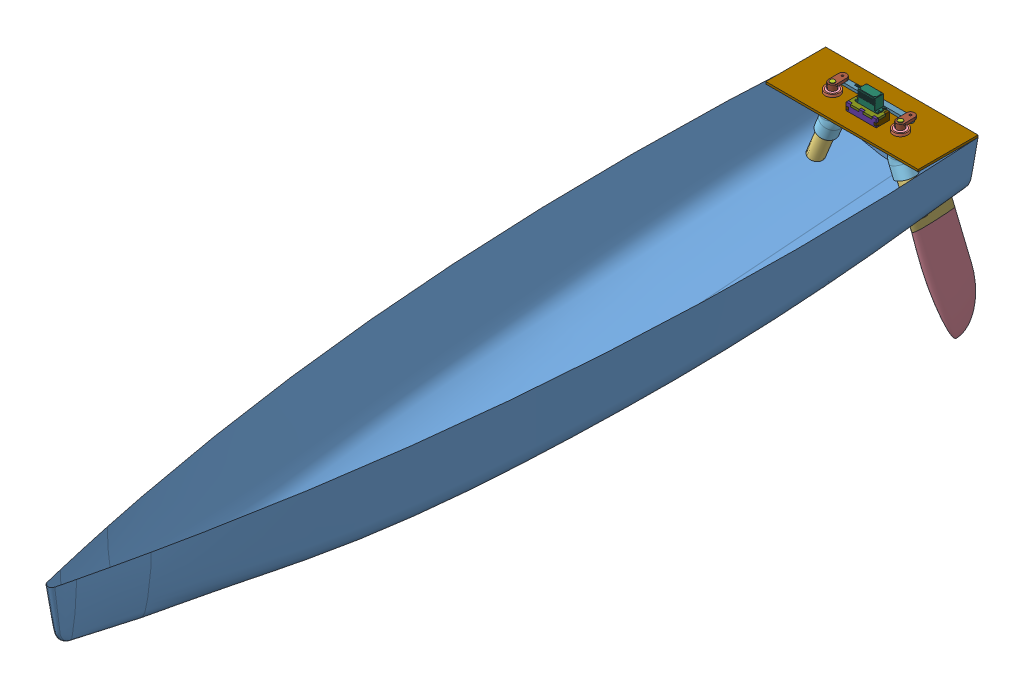
SolidWorks assembly TwinRudderSimpleLinkageDemo, configuration Default. Lengths in mm.
Overall size (425.79 407.28 1993.91).
46 component instances, 18 part files, 54 mates.
Components (placement in the parent):
- Hull-1: Hull [Default] at origin size (385.05 216.07 1993.91)
- BentRudderTube-1: BentRudderTube [Default] at (-0.635 -1.5875 0) size (85.08 167.37 46.84)
  - VerticalPVC-1: VerticalPVC [Default] at (-78.74 -37.7825 82.55) size (33.4 50.8 33.4)
  - AngledPVC-1: AngledPVC [Default] at (-120.3544 -145.3924 82.55) x (0.563065 -0.233229 0.792819) z (-0.732469 0.303399 0.609457) size (33.4 101.6 33.4)
  - UHMW_Bearing-1: UHMW_Bearing [Default] at (-93.1744 -79.7741 82.55) x (0.92154 -0.381714 -0.071118) z (0.065704 -0.027216 0.997468) size (26.92 12.7 26.92)
  - UHMW_Bearing-2: UHMW_Bearing [Default] at (-78.74 -19.9073 82.55) size (26.92 12.7 26.92)
  - UHMW_Bearing-3: UHMW_Bearing [Default] at (-78.74 0.3175 82.55) x (0.941661 0 -0.336564) z (0.336564 0 0.941661) size (26.92 12.7 26.92)
  - 4880K703_STANDARD-WALL WHITE PVC PIPE FITTING-1: 4880K703_STANDARD-WALL WHITE PVC PIPE FITTING [4880K703] at (-78.74 -44.9263 82.55) size (55.36 75.54 43.66)
  - UHMW_Bearing-4: UHMW_Bearing [Default] at (-120.3544 -145.3924 82.55) x (0.92388 -0.382683 0) z (0 0 1) size (26.92 12.7 26.92)
- 60625K950_Ball-And-Socket U-Joint-2: 60625K950_Ball-And-Socket U-Joint [Default] at (-79.375 -46.5138 82.55) x (0 -1 0) z (-0.999815 0 0.019253) size (52.04 20.86 29.99) (flexible)
  - 60625K950_BALL-AND-SOCKET U-JOINT-1: 60625K950_BALL-AND-SOCKET U-JOINT [60625K95] at origin size (29.78 20.07 20.64)
  - 60625K950_BALL-AND-SOCKET U-JOINT-2: 60625K950_BALL-AND-SOCKET U-JOINT [60625K95] x (-0.92388 0.007368 -0.382612) z (0.006807 0.999973 0.002819) size (29.78 20.07 20.64)
  - 60625K950_BALL-AND-SOCKET U-JOINT-3: 60625K950_BALL-AND-SOCKET U-JOINT [Ball] x (0.923905 0 0.382623) z (0.382623 0 -0.923905) size (7.85 16.72 16.72)
- RudderInputShaft-2: RudderInputShaft [Default] at (-79.375 -36.7347 82.55) x (-0.019253 0 -0.999815) z (0.999815 0 -0.019253) size (11.11 63.5 11.11)
- 60625K950_Ball-And-Socket U-Joint-1: 60625K950_Ball-And-Socket U-Joint [Default] at (79.375 -46.5138 82.55) x (0 -1 0) z (0.999815 0 -0.019253) size (52.04 20.86 29.99) (flexible)
  - 60625K950_BALL-AND-SOCKET U-JOINT-1: 60625K950_BALL-AND-SOCKET U-JOINT [60625K95] at origin size (29.78 20.07 20.64)
  - 60625K950_BALL-AND-SOCKET U-JOINT-2: 60625K950_BALL-AND-SOCKET U-JOINT [60625K95] x (-0.92388 0.007368 -0.382612) z (0.006807 0.999973 0.002819) size (29.78 20.07 20.64)
  - 60625K950_BALL-AND-SOCKET U-JOINT-3: 60625K950_BALL-AND-SOCKET U-JOINT [Ball] x (0.923905 0 0.382623) z (0.382623 0 -0.923905) size (7.85 16.72 16.72)
- BentRudderTube-3: BentRudderTube [Default] at (0.635 -1.5875 165.1) x (-1 0 0) z (0 0 -1) size (85.08 167.37 46.84)
  - VerticalPVC-1: VerticalPVC [Default] at (-78.74 -37.7825 82.55) size (33.4 50.8 33.4)
  - AngledPVC-1: AngledPVC [Default] at (-120.3544 -145.3924 82.55) x (0.563065 -0.233229 0.792819) z (-0.732469 0.303399 0.609457) size (33.4 101.6 33.4)
  - UHMW_Bearing-1: UHMW_Bearing [Default] at (-93.1744 -79.7741 82.55) x (0.92154 -0.381714 -0.071118) z (0.065704 -0.027216 0.997468) size (26.92 12.7 26.92)
  - UHMW_Bearing-2: UHMW_Bearing [Default] at (-78.74 -19.9073 82.55) size (26.92 12.7 26.92)
  - UHMW_Bearing-3: UHMW_Bearing [Default] at (-78.74 0.3175 82.55) x (0.941661 0 -0.336564) z (0.336564 0 0.941661) size (26.92 12.7 26.92)
  - 4880K703_STANDARD-WALL WHITE PVC PIPE FITTING-1: 4880K703_STANDARD-WALL WHITE PVC PIPE FITTING [4880K703] at (-78.74 -44.9263 82.55) size (55.36 75.54 43.66)
  - UHMW_Bearing-4: UHMW_Bearing [Default] at (-120.3544 -145.3924 82.55) x (0.92388 -0.382683 0) z (0 0 1) size (26.92 12.7 26.92)
- RudderOutputShaft-1: RudderOutputShaft [Default] at (-125.886 -158.8011 82.55) x (-0.923733 0.382623 0.017788) z (-0.016434 0.006807 -0.999842) size (11.11 111.76 11.11)
- RudderInputShaft-1: RudderInputShaft [Default] at (79.375 -36.7347 82.55) x (0.019253 0 0.999815) z (-0.999815 0 0.019253) size (11.11 63.5 11.11)
- RudderDeck-1: RudderDeck [Default] at (0 0 69.85) size (355.6 5.08 139.7)
- RudderServoHorn-1: RudderServoHorn [Default] at (0 12.4777 82.55) x (-0.999815 0 0.019253) z (0.019253 0 0.999815) size (12.7 6.35 36.7)
- RudderOutputLink-1: RudderOutputLink [Default] at (78.9129 18.8278 58.5544) x (-0.999815 0 0.019253) z (-0.019253 0 -0.999815) size (19.05 12.7 43.05)
- RudderOutputLink-2: RudderOutputLink [Default] at (-79.8371 18.8278 58.5544) x (-0.999815 0 0.019253) z (-0.019253 0 -0.999815) size (19.05 12.7 43.05)
- AssembledRudder-1: AssembledRudder [Default] at (121.3911 -146.9166 104.7715) x (-0.016434 -0.006807 -0.999842) z (0.382683 -0.92388 0) size (103.33 12.91 222.26)
  - RudderAdapter-1: RudderAdapter [Default] at origin size (101.93 12.41 38.1)
  - Rudder-1: Rudder [Default] at (0 0 19.05) size (103.33 12.91 203.25)
- AssembledRudder-2: AssembledRudder [Default] at (-120.6606 -147.2192 104.7715) x (-0.016434 0.006807 -0.999842) z (-0.382683 -0.92388 0) size (103.33 12.91 222.26)
  - RudderAdapter-1: RudderAdapter [Default] at origin size (101.93 12.41 38.1)
  - Rudder-1: Rudder [Default] at (0 0 19.05) size (103.33 12.91 203.25)
- RudderCouplerLink-2: RudderCouplerLink [Default] at (39.2254 12.4777 58.5544) x (-1 0 0) z (0 0 -1) size (92.08 6.35 12.7)
- RudderCouplerLink-3: RudderCouplerLink [Default] at (-40.1496 18.8278 58.5544) x (1 0 0) z (0 0 -1) size (92.08 6.35 12.7)
- RudderOutputShaft-4: RudderOutputShaft [Default] at (125.886 -158.8011 82.55) x (0.923733 0.382623 -0.017788) z (0.016434 0.006807 0.999842) size (11.11 111.76 11.11)
- small rudder servo-1: small rudder servo [Default] at (-10.25 51.7777 72.3) x (1 0 0) z (0 0 -1) size (61.75 42.9 20.5)
- RudderServoBracket-1: RudderServoBracket [Default] at (9.875 17.6978 104.8) x (-1 0 0) z (0 0 -1) size (69.85 5.08 31.75)
- ForwardServoShelfSupport-1: ForwardServoShelfSupport [Default] at (9.875 11.3477 99.72) size (69.85 22.86 5.08)
- SideServoShelfSupport-1: SideServoShelfSupport [Default] at (39.72 11.3477 86.385) x (0 0 -1) z (1 0 0) size (31.75 22.86 5.08)
- SideServoShelfSupport-2: SideServoShelfSupport [Default] at (-25.05 11.3477 86.385) x (0 0 -1) z (1 0 0) size (31.75 22.86 5.08)
Mates (geometry in assembly coordinates):
- Coincident12: coincident aligned: line of Hull-1 through (355.6 177.8 0) axis (0 -1 0); line of RudderDeck-1 through (177.8 0 0) axis (-1 0 0)
- Perpendicular1: perpendicular: plane of RudderDeck-1 through (0 5.08 69.85) normal (0 1 0); plane of Hull-1 through (0 0 0) normal (0 0 1)
- Coincident14: coincident: point of Hull-1; point of RudderDeck-1
- Concentric114: concentric anti-aligned: cylinder of BentRudderTube-3/VerticalPVC-1 through (79.375 11.43 82.55) axis (0 -1 0) radius 16.7005; cylinder of RudderDeck-1 through (79.375 0 82.55) axis (0 1 0) radius 16.7005
- Concentric115: concentric anti-aligned: cylinder of BentRudderTube-1/VerticalPVC-1 through (-79.375 11.43 82.55) axis (0 -1 0) radius 16.7005; cylinder of RudderDeck-1 through (-79.375 0 82.55) axis (0 1 0) radius 16.7005
- Coincident45: coincident aligned: plane of BentRudderTube-1/VerticalPVC-1 through (-79.375 11.43 82.55) normal (0 1 0); plane of BentRudderTube-3/VerticalPVC-1 through (79.375 11.43 82.55) normal (0 1 0)
- Distance1: distance = 6.35 mm aligned: plane of RudderDeck-1 through (0 5.08 69.85) normal (0 1 0); plane of BentRudderTube-3/VerticalPVC-1 through (79.375 11.43 82.55) normal (0 1 0)
- Concentric116: concentric aligned: cylinder of BentRudderTube-3/UHMW_Bearing-3 through (79.375 11.43 82.55) axis (0 -1 0) radius 5.5563; cylinder of RudderInputShaft-1 through (79.375 26.7653 82.55) axis (0 -1 0) radius 5.5563
- Concentric118: concentric aligned: cylinder of BentRudderTube-1/UHMW_Bearing-3 through (-79.375 11.43 82.55) axis (0 -1 0) radius 5.5563; cylinder of RudderInputShaft-2 through (-79.375 26.7653 82.55) axis (0 -1 0) radius 5.5563
- Concentric120: concentric anti-aligned: cylinder of 60625K950_Ball-And-Socket U-Joint-1/60625K950_BALL-AND-SOCKET U-JOINT-1 through (79.375 -36.7347 82.55) axis (0 1 0) radius 5.5563; cylinder of RudderInputShaft-1 through (79.375 26.7653 82.55) axis (0 -1 0) radius 5.5563
- Concentric121: concentric aligned: cylinder of 60625K950_Ball-And-Socket U-Joint-1/60625K950_BALL-AND-SOCKET U-JOINT-1 through (89.4061 -29.1147 82.3568) axis (-0.999815 0 0.019253) radius 1.5602; cylinder of RudderInputShaft-1 through (73.8198 -29.1147 82.657) axis (-0.999815 0 0.019253) radius 1.524
- Concentric122: concentric anti-aligned: cylinder of ? through (-79.375 -21.4947 82.55) axis (0 1 0) radius 9.525; cylinder of RudderInputShaft-2 through (-79.375 26.7653 82.55) axis (0 -1 0) radius 5.5563
- Concentric123: concentric aligned: cylinder of ? through (-89.4061 -29.1147 82.7432) axis (0.999815 0 -0.019253) radius 1.5602; cylinder of RudderInputShaft-2 through (-73.8198 -29.1147 82.443) axis (0.999815 0 -0.019253) radius 1.524
- Coincident48: coincident anti-aligned: plane of BentRudderTube-1/4880K703_STANDARD-WALL WHITE PVC PIPE FITTING-1 through (-79.375 -46.5138 82.55) normal (0 0 1); plane of BentRudderTube-3/4880K703_STANDARD-WALL WHITE PVC PIPE FITTING-1 through (79.375 -46.5138 82.55) normal (0 0 -1)
- Concentric124: concentric aligned: cylinder of 60625K950_Ball-And-Socket U-Joint-1/60625K950_BALL-AND-SOCKET U-JOINT-2 through (88.9494 -69.6283 82.55) axis (0.382683 -0.92388 0) radius 9.525; cylinder of RudderOutputShaft-4 through (83.1173 -55.5484 82.55) axis (0.382683 -0.92388 0) radius 5.5563
- Concentric125: concentric aligned: cylinder of 60625K950_Ball-And-Socket U-Joint-1/60625K950_BALL-AND-SOCKET U-JOINT-2 through (85.8684 -62.6566 72.5186) axis (0.016434 0.006807 0.999842) radius 1.5602; cylinder of RudderOutputShaft-4 through (86.1246 -62.5505 88.1054) axis (0.016434 0.006807 0.999842) radius 1.524
- Concentric126: concentric aligned: cylinder of ? through (-88.9494 -69.6283 82.55) axis (-0.382683 -0.92388 0) radius 9.525; cylinder of RudderOutputShaft-1 through (-83.1173 -55.5484 82.55) axis (-0.382683 -0.92388 0) radius 5.5563
- Concentric127: concentric aligned: cylinder of ? through (-85.8684 -62.6566 92.5814) axis (-0.016434 0.006807 -0.999842) radius 1.5602; cylinder of RudderOutputShaft-1 through (-86.1246 -62.5505 76.9946) axis (-0.016434 0.006807 -0.999842) radius 1.524
- Concentric128: concentric aligned: cylinder of BentRudderTube-1/UHMW_Bearing-1 through (-88.9494 -69.6283 82.55) axis (-0.382683 -0.92388 0) radius 13.462; cylinder of RudderOutputShaft-1 through (-83.1173 -55.5484 82.55) axis (-0.382683 -0.92388 0) radius 5.5563
- Concentric129: concentric aligned: cylinder of BentRudderTube-3/UHMW_Bearing-1 through (88.9494 -69.6283 82.55) axis (0.382683 -0.92388 0) radius 13.462; cylinder of RudderOutputShaft-4 through (83.1173 -55.5484 82.55) axis (0.382683 -0.92388 0) radius 5.5563
- Concentric130: concentric anti-aligned: cylinder of AssembledRudder-1/RudderAdapter-1 through (125.886 -158.8011 82.55) axis (-0.382683 0.92388 0) radius 5.5563; cylinder of RudderOutputShaft-4 through (83.1173 -55.5484 82.55) axis (0.382683 -0.92388 0) radius 5.5563
- Concentric131: concentric aligned: cylinder of AssembledRudder-1/RudderAdapter-1 through (123.8212 -152.7832 104.7715) axis (0.016434 0.006807 0.999842) radius 2.1526; cylinder of RudderOutputShaft-4 through (123.5472 -152.8967 88.1054) axis (0.016434 0.006807 0.999842) radius 1.524
- Concentric132: concentric anti-aligned: cylinder of RudderOutputShaft-1 through (-83.1173 -55.5484 82.55) axis (-0.382683 -0.92388 0) radius 5.5563; cylinder of AssembledRudder-2/RudderAdapter-1 through (-125.886 -158.8011 82.55) axis (0.382683 0.92388 0) radius 5.5563
- Concentric133: concentric anti-aligned: cylinder of RudderOutputShaft-1 through (-123.5472 -152.8967 76.9946) axis (-0.016434 0.006807 -0.999842) radius 1.524; cylinder of AssembledRudder-2/RudderAdapter-1 through (-123.0907 -153.0858 104.7715) axis (0.016434 -0.006807 0.999842) radius 2.1526
- Concentric134: concentric aligned: cylinder of RudderInputShaft-1 through (79.375 26.7653 82.55) axis (0 -1 0) radius 5.5563; cylinder of RudderOutputLink-1 through (79.375 25.1777 82.55) axis (0 -1 0) radius 9.525
- Concentric135: concentric anti-aligned: cylinder of RudderInputShaft-1 through (73.8198 22.0028 82.657) axis (-0.999815 0 0.019253) radius 1.524; cylinder of RudderOutputLink-1 through (88.8982 22.0028 82.3666) axis (0.999815 0 -0.019253) radius 1.8288
- Concentric136: concentric aligned: cylinder of RudderInputShaft-2 through (-79.375 26.7653 82.55) axis (0 -1 0) radius 5.5563; cylinder of RudderOutputLink-2 through (-79.375 25.1777 82.55) axis (0 -1 0) radius 9.525
- Concentric137: concentric aligned: cylinder of RudderInputShaft-2 through (-73.8198 22.0028 82.443) axis (0.999815 0 -0.019253) radius 1.524; cylinder of RudderOutputLink-2 through (-69.8518 22.0028 82.3666) axis (0.999815 0 -0.019253) radius 1.8288
- Concentric139: concentric aligned: circle of RudderOutputLink-1; cylinder of RudderCouplerLink-2 through (78.9129 18.8278 58.5544) axis (0 1 0) radius 2.3813
- Coincident56: coincident anti-aligned: plane of RudderDeck-1 through (0 5.08 69.85) normal (0 1 0); plane of ? through (20.5008 5.08 69.55) normal (0 -1 0)
- Coincident57: coincident anti-aligned: plane of RudderDeck-1 through (14.0008 0 67.55) normal (0 0 1); plane of ? through (-58.4992 10.08 67.55) normal (0 0 -1)
- Coincident59: coincident anti-aligned: plane of RudderDeck-1 through (14.0008 0 67.55) normal (-1 0 0); plane of ? through (14.0008 -35.92 97.05) normal (1 0 0)
- Coincident60: coincident aligned: line of RudderDeck-1 through (-177.8 5.08 139.7) axis (1 0 0); line of ? through (-177.8 5.08 139.7) axis (1 0 0)
- Coincident61: coincident anti-aligned: line of RudderDeck-1 through (177.8 5.08 139.7) axis (0 0 -1); line of ? through (177.8 5.08 139.7) axis (0 0 1)
- Concentric146: concentric aligned: cylinder of RudderServoHorn-1 through (0.0008 31.5278 82.55) axis (0 1 0) radius 3.175; circle of ?
- Coincident64: coincident anti-aligned: plane of RudderCouplerLink-2 through (78.9129 18.8278 58.5544) normal (0 1 0); plane of RudderOutputLink-1 through (79.375 18.8278 82.55) normal (0 -1 0)
- Coincident65: coincident anti-aligned: circle of RudderCouplerLink-2; circle of RudderCouplerLink-3
- Concentric147: concentric anti-aligned: cylinder of RudderOutputLink-2 through (-79.8371 25.1777 58.5544) axis (0 1 0) radius 2.3813; cylinder of RudderCouplerLink-3 through (-79.8371 12.4777 58.5544) axis (0 -1 0) radius 2.3813
- Concentric148: concentric aligned: cylinder of RudderServoHorn-1 through (-0.4621 6.1278 58.5544) axis (0 -1 0) radius 2.0193; cylinder of RudderCouplerLink-3 through (-0.4621 12.4777 58.5544) axis (0 -1 0) radius 2.0193
- Concentric150: concentric anti-aligned: cylinder of RudderServoHorn-1 through (0 6.1278 82.55) axis (0 1 0) radius 3.175; circle of small rudder servo-1
- Coincident67: coincident anti-aligned: plane of RudderServoHorn-1 through (-0.4621 12.4777 58.5544) normal (0 1 0); plane of small rudder servo-1 through (0 12.4777 82.55) normal (0 -1 0)
- Distance3: distance = 82.55 mm: cylinder of small rudder servo-1 through (0 12.9778 82.55) axis (0 1 0) radius 6.725; plane of RudderDeck-1 through (177.8 5.08 0) normal (0 0 -1)
- Coincident70: coincident anti-aligned: plane of RudderServoHorn-1 through (-0.4621 12.4777 58.5544) normal (0 1 0); plane of RudderCouplerLink-2 through (78.9129 12.4777 58.5544) normal (0 -1 0)
- Distance4: distance = 177.8 mm: plane of RudderDeck-1 through (177.8 5.08 139.7) normal (1 0 0); cylinder of small rudder servo-1 through (0 14.9778 82.55) axis (0 1 0) radius 9.3
- Perpendicular2: perpendicular: plane of RudderDeck-1 through (177.8 5.08 0) normal (0 0 -1); plane of small rudder servo-1 through (-10.25 17.9778 72.3) normal (-1 0 0)
- Coincident71: coincident anti-aligned: plane of small rudder servo-1 through (-3.45 22.7778 92.8) normal (0 -1 0); plane of RudderServoBracket-1 through (9.875 22.7778 104.8) normal (0 1 0)
- Concentric151: concentric aligned: cylinder of small rudder servo-1 through (-15.175 22.8777 77.3) axis (0 1 0) radius 2.25; cylinder of RudderServoBracket-1 through (-15.175 22.7778 77.3) axis (0 1 0) radius 1.1906
- Concentric152: concentric aligned: cylinder of small rudder servo-1 through (34.925 22.8777 77.3) axis (0 1 0) radius 2.25; cylinder of RudderServoBracket-1 through (34.925 22.7778 77.3) axis (0 1 0) radius 1.1906
- Coincident72: coincident aligned: line of RudderServoBracket-1 through (14.6375 22.7778 99.72) axis (-1 0 0); line of ForwardServoShelfSupport-1 through (14.6375 22.7778 99.72) axis (-1 0 0)
- Coincident73: coincident anti-aligned: line of RudderServoBracket-1 through (14.6375 22.7778 104.8) axis (0 0 -1); line of ForwardServoShelfSupport-1 through (14.6375 22.7778 99.72) axis (0 0 1)
- Coincident74: coincident aligned: line of RudderServoBracket-1 through (39.72 22.7778 73.05) axis (0 0 1); line of SideServoShelfSupport-1 through (39.72 22.7778 73.05) axis (0 0 1)
- Coincident75: coincident anti-aligned: line of RudderServoBracket-1 through (39.72 22.7778 82.575) axis (1 0 0); line of SideServoShelfSupport-1 through (44.8 22.7778 82.575) axis (-1 0 0)
- Coincident76: coincident anti-aligned: line of RudderServoBracket-1 through (-19.97 22.7778 82.575) axis (0 0 -1); line of SideServoShelfSupport-2 through (-19.97 22.7778 73.05) axis (0 0 1)
- Coincident77: coincident anti-aligned: line of RudderServoBracket-1 through (-25.05 22.7778 82.575) axis (1 0 0); line of SideServoShelfSupport-2 through (-19.97 22.7778 82.575) axis (-1 0 0)
